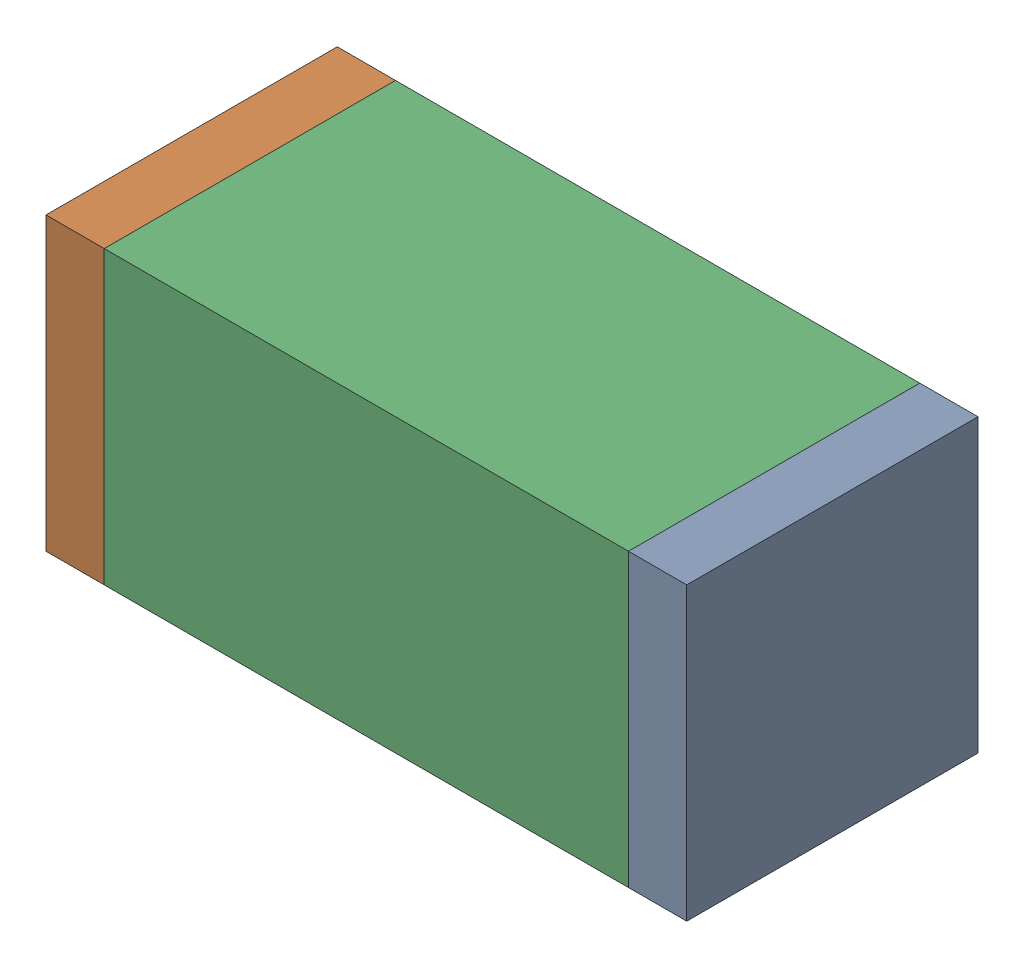
SolidWorks assembly C80, configuration Default. Lengths in mm.
Overall size (1.1 0.5 0.5).
6 component instances, 2 part files, 0 mates.
Components (placement in the parent):
- 810156080-1: 810156080 [Default] at (124.35 60.95 0) size (0.1 0.5 0.5)
  - Extruded_5-1: Extruded_5 [Default] at origin size (0.1 0.5 0.5)
- 810156080-2: 810156080 [Default] at (123.35 60.95 0) size (0.1 0.5 0.5)
  - Extruded_5-1: Extruded_5 [Default] at origin size (0.1 0.5 0.5)
- 836749680-1: 836749680 [Default] at (123.85 60.95 0) size (0.9 0.5 0.5)
  - Extruded_4-1: Extruded_4 [Default] at origin size (0.9 0.5 0.5)
